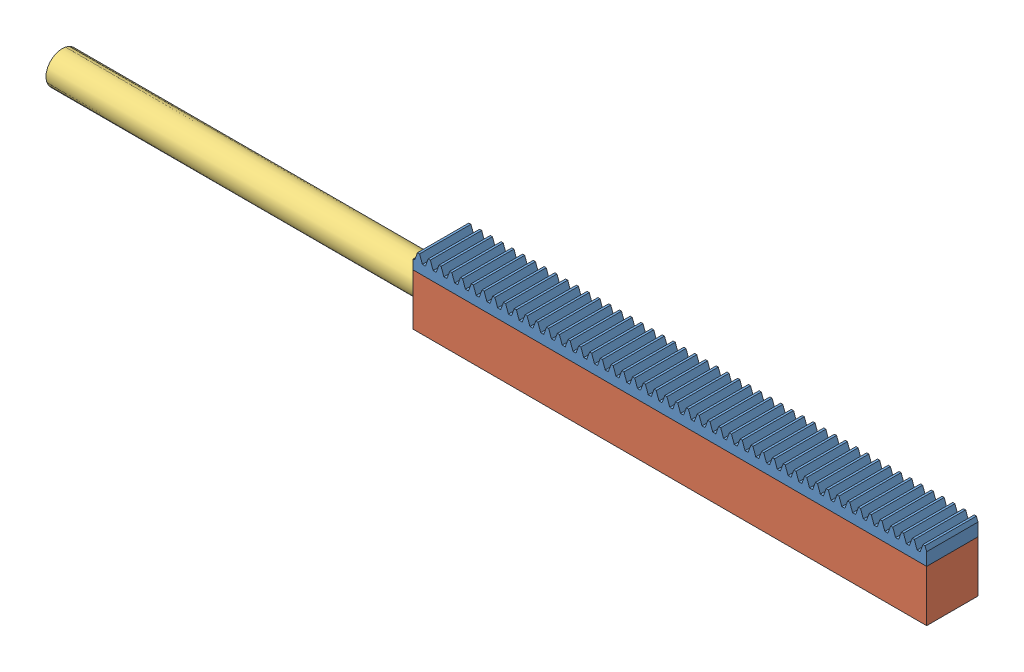
SolidWorks assembly rackblock assembly, configuration Default. Lengths in mm.
Overall size (260 20 15).
3 component instances, 3 part files, 6 mates.
Components (placement in the parent):
- rack spur rectangular_am-1: rack spur rectangular_am [Metric - Rack-spur - rectangular 1M 20PA 15mmFW 4PH 150L---SAll] at (-75 15 7.5) size (150 5 15)
- rackblock-1: rackblock [Default] at origin size (150 15 15)
- barrel-2: barrel [Default] at (-185 7.5 0) x (1 0 0) z (0 -0.983109 0.183021) size (250 9.53 9.53)
Mates (geometry in assembly coordinates):
- Coincident1: coordinate: point of rackblock-1
- Coincident2: coincident anti-aligned: plane of rack spur rectangular_am-1 through (-75 15 -7.5) normal (0 -1 0); plane of rackblock-1 through (0 15 0) normal (0 1 0)
- Coincident3: coincident aligned: plane of rack spur rectangular_am-1 through (-75 15 -7.5) normal (-1 0 0); plane of rackblock-1 through (-75 15 7.5) normal (-1 0 0)
- Coincident4: coincident aligned: plane of rack spur rectangular_am-1 through (-75 20 7.5) normal (0 0 1); plane of rackblock-1 through (-75 15 7.5) normal (0 0 1)
- Concentric1: concentric aligned: cylinder of rackblock-1 through (88.6118 7.5 0) axis (-1 0 0) radius 4.8125; cylinder of barrel-2 through (65 7.5 0) axis (-1 0 0) radius 4.7625
- Coincident5: coincident anti-aligned: circle of rackblock-1; plane of barrel-2 through (65 7.5 0) normal (1 0 0)
